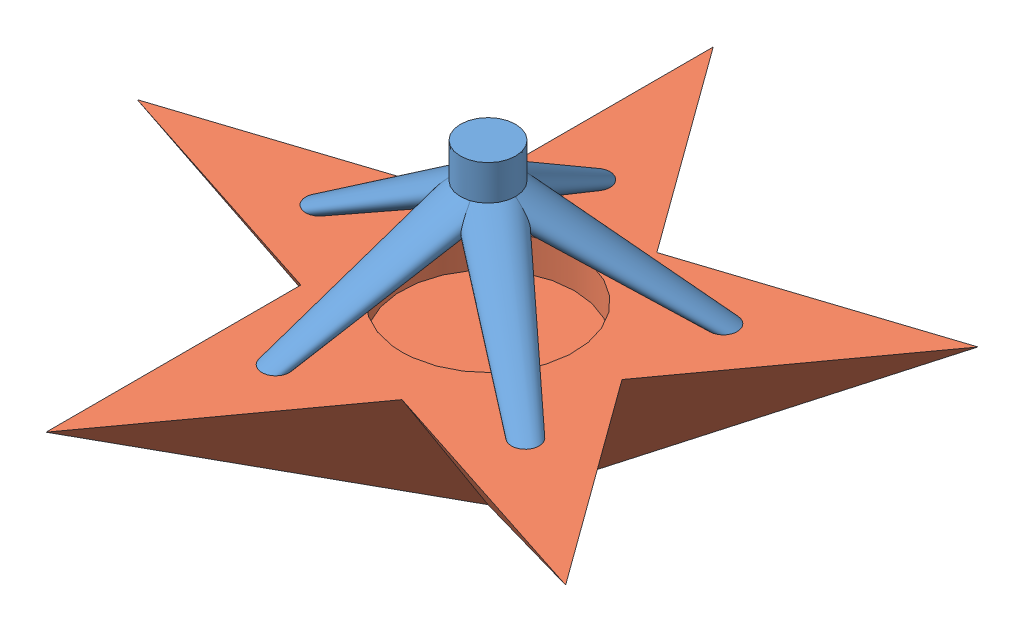
SolidWorks assembly casting_assembly, configuration Default. Lengths in mm.
Overall size (72.13 22.87 61.77).
2 component instances, 2 part files, 3 mates.
Components (placement in the parent):
- star_casting_sprues-1: star_casting_sprues [Default] at (8.2969 10.4277 22.5007) size (24.49 10.17 25.75)
- star_5pt18d_07042013-1: star_5pt18d_07042013 [Default] at (8.2969 10.4277 22.5007) x (-1 0 0) z (0 0 1) size (72.13 12.71 61.77)
Mates (geometry in assembly coordinates):
- Coincident8: coincident: point of star_casting_sprues-1; point of star_5pt18d_07042013-1
- Coincident9: coincident: line of star_casting_sprues-1 through (8.2969 10.4277 22.5007) axis (-1 0 0); line of star_5pt18d_07042013-1 through (8.2969 10.4277 22.5007) axis (-1 0 0)
- Coincident10: coincident aligned: circle of star_casting_sprues-1; plane of star_5pt18d_07042013-1 through (8.2969 10.4277 22.5007) normal (0 1 0)
